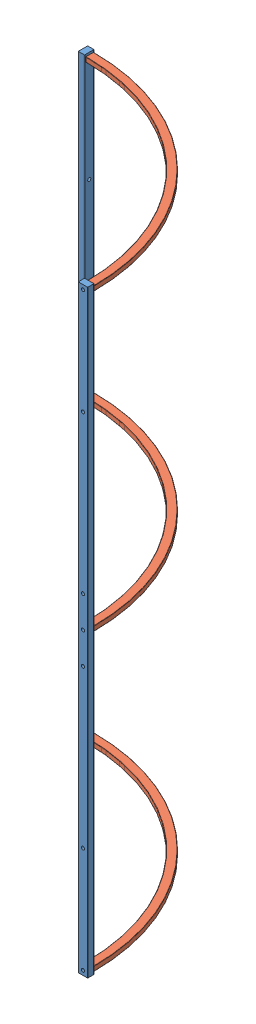
SolidWorks assembly 02Rxx-xxx_Ram(02R90-190)-1, configuration Default. Lengths in mm.
Overall size (664 1900 664).
5 component instances, 2 part files, 0 mates.
Components (placement in the parent):
- 20x30(1900)-1-1: 20x30(1900)-1 [Default] at origin size (20 1900 30)
- 20x30(1900)-1-2: 20x30(1900)-1 [Default] at (639 0 639) x (0 0 -1) z (1 0 0) size (20 1900 30)
- 2515100-R90(2515100-R90)-1: 2515100-R90(2515100-R90) [Default] at (10 -935.5 629) x (0 0 1) z (-1 0 0) size (643 15 643)
- 2515100-R90(2515100-R90)-2: 2515100-R90(2515100-R90) [Default] at (10 0 629) x (0 0 1) z (-1 0 0) size (643 15 643)
- 2515100-R90(2515100-R90)-3: 2515100-R90(2515100-R90) [Default] at (10 935.5 629) x (0 0 1) z (-1 0 0) size (643 15 643)
